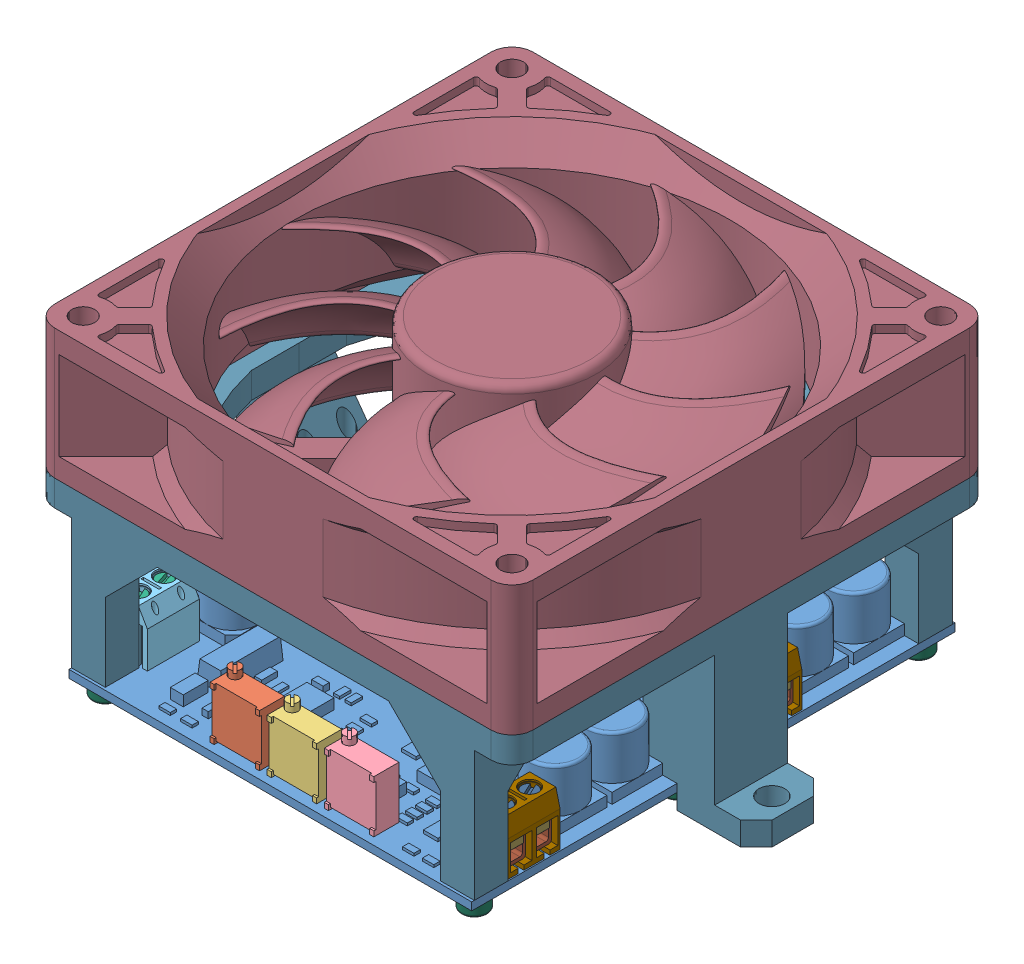
SolidWorks assembly Ensamblaje5, configuration Predeterminado. Lengths in mm.
Overall size (103.83 62.67 98.14).
56 component instances, 15 part files, 30 mates.
Components (placement in the parent):
- LTC 3780 Mudule v11-1: LTC 3780 Mudule v11 [Predeterminado] at (-9.7259 -4.7467 77.5) x (1 0 0) z (0 1 0) size (77.5 46.5 15.68)
  - LTC 3780 Mudule-1: LTC 3780 Mudule [Predeterminado] at origin size (77.5 46.5 14)
  - Trimpot_3296W v1-1: Trimpot_3296W v1 [Predeterminado] at (-8.265 -19.415 0) x (-1 0 0) z (0 0 1) size (9.53 4.83 14.15)
  - Trimpot_3296W v1 (1)-1: Trimpot_3296W v1 (1) [Predeterminado] at (2.735 -19.415 0) x (-1 0 0) z (0 0 1) size (9.53 4.83 14.15)
  - Trimpot_3296W v1 (2)-1: Trimpot_3296W v1 (2) [Predeterminado] at (13.735 -19.415 0) x (-1 0 0) z (0 0 1) size (9.53 4.83 14.15)
  - DG306-5 v2-1: DG306-5 v2 [Predeterminado] at (0 0 17) size (7.6 10.62 14.13)
    - Case-1: Case [Predeterminado] at (-38.5 -6 -17) x (0 -1 0) z (-1 0 0) size (10.62 10 7.6)
    - Screw-1: Screw [Predeterminado] at (-35.14 -8.5 -13.12) x (0.304322 -0.952569 0) z (-0.952569 -0.304322 0) size (3.38 5.66 3.38)
    - Terminal-1: Terminal [Predeterminado] at (-32.9 -6.55 -16.126) x (0 -1 0) z (-1 0 0) size (3.9 9.8 4.48)
    - Spring-1: Spring [Predeterminado] at (-37.5 -7.135 -13.226) x (0 -1 0) z (-1 0 0) size (2.73 2.2 5.76)
    - Screw-2: Screw [Predeterminado] at (-35.14 -13.5 -13.12) x (0.425528 -0.904945 0) z (-0.904945 -0.425528 0) size (3.38 5.66 3.38)
    - Terminal-2: Terminal [Predeterminado] at (-32.9 -11.55 -16.126) x (0 -1 0) z (-1 0 0) size (3.9 9.8 4.48)
    - Spring-2: Spring [Predeterminado] at (-37.5 -12.135 -13.226) x (0 -1 0) z (-1 0 0) size (2.73 2.2 5.76)
  - DG306-5 v2 (1)-1: DG306-5 v2 (1) [Predeterminado] at origin size (7.6 10.62 14.13)
    - Case (1)-1: Case (1) [Predeterminado] at (38.5 -16 0) x (0 1 0) z (1 0 0) size (10.62 10 7.6)
    - Screw (1)-1: Screw (1) [Predeterminado] at (35.14 -13.5 3.88) x (-0.304322 0.952569 0) z (0.952569 0.304322 0) size (3.38 5.66 3.38)
    - Terminal (1)-1: Terminal (1) [Predeterminado] at (32.9 -15.45 0.874) x (0 1 0) z (1 0 0) size (3.9 9.8 4.48)
    - Spring (1)-1: Spring (1) [Predeterminado] at (37.5 -14.865 3.774) x (0 1 0) z (1 0 0) size (2.73 2.2 5.76)
    - Screw (1)-2: Screw (1) [Predeterminado] at (35.14 -8.5 3.88) x (-0.425528 0.904945 0) z (0.904945 0.425528 0) size (3.38 5.66 3.38)
    - Terminal (1)-2: Terminal (1) [Predeterminado] at (32.9 -10.45 0.874) x (0 1 0) z (1 0 0) size (3.9 9.8 4.48)
    - Spring (1)-2: Spring (1) [Predeterminado] at (37.5 -9.865 3.774) x (0 1 0) z (1 0 0) size (2.73 2.2 5.76)
- LTC 3780 Mudule v11-2: LTC 3780 Mudule v11 [Predeterminado] at (-9.7259 -4.7467 124) x (1 0 0) z (0 1 0) size (77.5 46.5 15.68)
  - LTC 3780 Mudule-1: LTC 3780 Mudule [Predeterminado] at origin size (77.5 46.5 14)
  - Trimpot_3296W v1-1: Trimpot_3296W v1 [Predeterminado] at (-8.265 -19.415 0) x (-1 0 0) z (0 0 1) size (9.53 4.83 14.15)
  - Trimpot_3296W v1 (1)-1: Trimpot_3296W v1 (1) [Predeterminado] at (2.735 -19.415 0) x (-1 0 0) z (0 0 1) size (9.53 4.83 14.15)
  - Trimpot_3296W v1 (2)-1: Trimpot_3296W v1 (2) [Predeterminado] at (13.735 -19.415 0) x (-1 0 0) z (0 0 1) size (9.53 4.83 14.15)
  - DG306-5 v2-1: DG306-5 v2 [Predeterminado] at (0 0 17) size (7.6 10.62 14.13)
    - Case-1: Case [Predeterminado] at (-38.5 -6 -17) x (0 -1 0) z (-1 0 0) size (10.62 10 7.6)
    - Screw-1: Screw [Predeterminado] at (-35.14 -8.5 -13.12) x (0.304322 -0.952569 0) z (-0.952569 -0.304322 0) size (3.38 5.66 3.38)
    - Terminal-1: Terminal [Predeterminado] at (-32.9 -6.55 -16.126) x (0 -1 0) z (-1 0 0) size (3.9 9.8 4.48)
    - Spring-1: Spring [Predeterminado] at (-37.5 -7.135 -13.226) x (0 -1 0) z (-1 0 0) size (2.73 2.2 5.76)
    - Screw-2: Screw [Predeterminado] at (-35.14 -13.5 -13.12) x (0.425528 -0.904945 0) z (-0.904945 -0.425528 0) size (3.38 5.66 3.38)
    - Terminal-2: Terminal [Predeterminado] at (-32.9 -11.55 -16.126) x (0 -1 0) z (-1 0 0) size (3.9 9.8 4.48)
    - Spring-2: Spring [Predeterminado] at (-37.5 -12.135 -13.226) x (0 -1 0) z (-1 0 0) size (2.73 2.2 5.76)
  - DG306-5 v2 (1)-1: DG306-5 v2 (1) [Predeterminado] at origin size (7.6 10.62 14.13)
    - Case (1)-1: Case (1) [Predeterminado] at (38.5 -16 0) x (0 1 0) z (1 0 0) size (10.62 10 7.6)
    - Screw (1)-1: Screw (1) [Predeterminado] at (35.14 -13.5 3.88) x (-0.304322 0.952569 0) z (0.952569 0.304322 0) size (3.38 5.66 3.38)
    - Terminal (1)-1: Terminal (1) [Predeterminado] at (32.9 -15.45 0.874) x (0 1 0) z (1 0 0) size (3.9 9.8 4.48)
    - Spring (1)-1: Spring (1) [Predeterminado] at (37.5 -14.865 3.774) x (0 1 0) z (1 0 0) size (2.73 2.2 5.76)
    - Screw (1)-2: Screw (1) [Predeterminado] at (35.14 -8.5 3.88) x (-0.425528 0.904945 0) z (0.904945 0.425528 0) size (3.38 5.66 3.38)
    - Terminal (1)-2: Terminal (1) [Predeterminado] at (32.9 -10.45 0.874) x (0 1 0) z (1 0 0) size (3.9 9.8 4.48)
    - Spring (1)-2: Spring (1) [Predeterminado] at (37.5 -9.865 3.774) x (0 1 0) z (1 0 0) size (2.73 2.2 5.76)
- 92mm FAN-1: 92mm FAN [Default] at (-9.7259 50.2533 100.75) x (1 0 0) z (0 0 -1) size (98.99 31.34 98.14)
- soporte-1: soporte [Predeterminado] at (-9.7259 20.2533 100.75) size (100 34.5 92)
- Tornillo M3x10_2-1: Tornillo M3x10_2 [Predeterminado] at (-45.2259 3.7533 97) x (1 0 0) z (0 -1 0) size (5 5 13)
- Tornillo M3x10_2-2: Tornillo M3x10_2 [Predeterminado] at (25.7741 3.7533 58) x (1 0 0) z (0 -1 0) size (5 5 13)
- Tornillo M3x10_2-3: Tornillo M3x10_2 [Predeterminado] at (-45.2259 3.7533 143.5) x (1 0 0) z (0 -1 0) size (5 5 13)
- Tornillo M3x10_2-4: Tornillo M3x10_2 [Predeterminado] at (25.7741 3.7533 143.5) x (1 0 0) z (0 -1 0) size (5 5 13)
- Tornillo M3x10_2-5: Tornillo M3x10_2 [Predeterminado] at (25.7741 3.7533 97) x (1 0 0) z (0 -1 0) size (5 5 13)
- Tornillo M3x10_2-6: Tornillo M3x10_2 [Predeterminado] at (25.7741 3.7533 104.5) x (1 0 0) z (0 -1 0) size (5 5 13)
- Tornillo M3x10_2-7: Tornillo M3x10_2 [Predeterminado] at (-45.2259 3.7533 58) x (1 0 0) z (0 -1 0) size (5 5 13)
- Tornillo M3x10_2-8: Tornillo M3x10_2 [Predeterminado] at (-45.2259 3.7533 104.5) x (1 0 0) z (0 -1 0) size (5 5 13)
- Tornillo M3x10_2-9: Tornillo M3x10_2 [Predeterminado] at (-50.9759 19.2533 142) x (1 0 0) z (0 1 0) size (5 5 13)
- Tornillo M3x10_2-10: Tornillo M3x10_2 [Predeterminado] at (31.5241 19.2533 59.5) x (1 0 0) z (0 1 0) size (5 5 13)
- Tornillo M3x10_2-11: Tornillo M3x10_2 [Predeterminado] at (31.5241 19.2533 142) x (1 0 0) z (0 1 0) size (5 5 13)
- Tornillo M3x10_2-12: Tornillo M3x10_2 [Predeterminado] at (-50.9759 19.2533 59.5) x (1 0 0) z (0 1 0) size (5 5 13)
Mates (geometry in assembly coordinates):
- Ancho1: width anti-aligned: plane of 92mm FAN-1 through (36.2741 25.2533 54.75) normal (0 0 -1); plane of 92mm FAN-1 through (36.2741 25.2533 146.75) normal (0 0 1); plane of LTC 3780 Mudule v11-2/LTC 3780 Mudule-1 through (-48.4759 85.6331 147.25) normal (0 0 1); plane of LTC 3780 Mudule v11-1/LTC 3780 Mudule-1 through (-48.4759 85.6331 54.25) normal (0 0 -1)
- Ancho2: width anti-aligned: plane of 92mm FAN-1 through (-55.7259 25.2533 54.75) normal (-1 0 0); plane of 92mm FAN-1 through (36.2741 25.2533 54.75) normal (1 0 0); plane of LTC 3780 Mudule v11-2/LTC 3780 Mudule-1 through (29.0241 85.6331 100.75) normal (1 0 0); plane of LTC 3780 Mudule v11-2/LTC 3780 Mudule-1 through (-48.4759 85.6331 100.75) normal (-1 0 0)
- Distancia1: distance = 30 mm anti-aligned: plane of 92mm FAN-1 through (-9.7259 25.2533 100.75) normal (0 -1 0); plane of LTC 3780 Mudule v11-1/LTC 3780 Mudule-1 through (-9.7259 -4.7467 77.5) normal (0 1 0)
- Coincidente1: coincident anti-aligned: plane of 92mm FAN-1 through (-9.7259 25.2533 100.75) normal (0 -1 0); plane of soporte-1 through (-9.7259 25.2533 100.75) normal (0 1 0)
- Coincidente2: coincident aligned: plane of 92mm FAN-1 through (-55.7259 25.2533 54.75) normal (-1 0 0); plane of soporte-1 through (-55.7259 25.2533 146.75) normal (-1 0 0)
- Coincidente3: coincident aligned: plane of 92mm FAN-1 through (36.2741 25.2533 54.75) normal (0 0 -1); plane of soporte-1 through (-55.7259 25.2533 54.75) normal (0 0 -1)
- Coincidente4: coincident aligned: plane of Tornillo M3x10_2-6 through (25.7741 -9.2467 104.5) normal (0 -1 0); plane of Tornillo M3x10_2-7 through (-45.2259 -9.2467 58) normal (0 -1 0)
- Coincidente5: coincident aligned: plane of Tornillo M3x10_2-5 through (25.7741 -9.2467 97) normal (0 -1 0); plane of Tornillo M3x10_2-7 through (-45.2259 -9.2467 58) normal (0 -1 0)
- Coincidente6: coincident aligned: plane of Tornillo M3x10_2-7 through (-45.2259 -9.2467 58) normal (0 -1 0); plane of Tornillo M3x10_2-8 through (-45.2259 -9.2467 104.5) normal (0 -1 0)
- Coincidente7: coincident aligned: plane of Tornillo M3x10_2-3 through (-45.2259 -9.2467 143.5) normal (0 -1 0); plane of Tornillo M3x10_2-8 through (-45.2259 -9.2467 104.5) normal (0 -1 0)
- Coincidente8: coincident aligned: plane of Tornillo M3x10_2-1 through (-45.2259 -9.2467 97) normal (0 -1 0); plane of Tornillo M3x10_2-3 through (-45.2259 -9.2467 143.5) normal (0 -1 0)
- Coincidente9: coincident aligned: plane of Tornillo M3x10_2-1 through (-45.2259 -9.2467 97) normal (0 -1 0); plane of Tornillo M3x10_2-4 through (25.7741 -9.2467 143.5) normal (0 -1 0)
- Coincidente10: coincident aligned: plane of Tornillo M3x10_2-2 through (25.7741 -9.2467 58) normal (0 -1 0); plane of Tornillo M3x10_2-4 through (25.7741 -9.2467 143.5) normal (0 -1 0)
- Coincidente11: coincident anti-aligned: plane of LTC 3780 Mudule v11-2/LTC 3780 Mudule-1 through (-9.7259 -6.2467 124) normal (0 -1 0); plane of Tornillo M3x10_2-3 through (-45.2259 -6.2467 143.5) normal (0 1 0)
- Concéntrica1: concentric anti-aligned: cylinder of LTC 3780 Mudule v11-2/LTC 3780 Mudule-1 through (-45.2259 85.6331 143.5) axis (0 -1 0) radius 1.9; cylinder of Tornillo M3x10_2-3 through (-45.2259 -9.2467 143.5) axis (0 1 0) radius 2.5
- Concéntrica2: concentric anti-aligned: cylinder of LTC 3780 Mudule v11-2/LTC 3780 Mudule-1 through (-45.2259 85.6331 104.5) axis (0 -1 0) radius 1.9; cylinder of Tornillo M3x10_2-8 through (-45.2259 -9.2467 104.5) axis (0 1 0) radius 2.5
- Concéntrica3: concentric anti-aligned: cylinder of LTC 3780 Mudule v11-1/LTC 3780 Mudule-1 through (-45.2259 85.6331 97) axis (0 -1 0) radius 1.9; cylinder of Tornillo M3x10_2-1 through (-45.2259 -9.2467 97) axis (0 1 0) radius 2.5
- Concéntrica4: concentric anti-aligned: cylinder of LTC 3780 Mudule v11-1/LTC 3780 Mudule-1 through (-45.2259 85.6331 58) axis (0 -1 0) radius 1.9; cylinder of Tornillo M3x10_2-7 through (-45.2259 -9.2467 58) axis (0 1 0) radius 2.5
- Concéntrica5: concentric anti-aligned: cylinder of LTC 3780 Mudule v11-2/LTC 3780 Mudule-1 through (25.7741 85.6331 104.5) axis (0 -1 0) radius 1.9; cylinder of Tornillo M3x10_2-6 through (25.7741 -9.2467 104.5) axis (0 1 0) radius 2.5
- Concéntrica6: concentric anti-aligned: cylinder of LTC 3780 Mudule v11-2/LTC 3780 Mudule-1 through (25.7741 85.6331 143.5) axis (0 -1 0) radius 1.9; cylinder of Tornillo M3x10_2-4 through (25.7741 -9.2467 143.5) axis (0 1 0) radius 2.5
- Concéntrica7: concentric anti-aligned: cylinder of LTC 3780 Mudule v11-1/LTC 3780 Mudule-1 through (25.7741 85.6331 97) axis (0 -1 0) radius 1.9; cylinder of Tornillo M3x10_2-5 through (25.7741 -9.2467 97) axis (0 1 0) radius 2.5
- Concéntrica8: concentric anti-aligned: cylinder of LTC 3780 Mudule v11-1/LTC 3780 Mudule-1 through (25.7741 85.6331 58) axis (0 -1 0) radius 1.9; cylinder of Tornillo M3x10_2-2 through (25.7741 -9.2467 58) axis (0 1 0) radius 2.5
- Coincidente12: coincident aligned: plane of Tornillo M3x10_2-10 through (31.5241 32.2533 59.5) normal (0 1 0); plane of Tornillo M3x10_2-11 through (31.5241 32.2533 142) normal (0 1 0)
- Coincidente13: coincident aligned: plane of Tornillo M3x10_2-10 through (31.5241 32.2533 59.5) normal (0 1 0); plane of Tornillo M3x10_2-12 through (-50.9759 32.2533 59.5) normal (0 1 0)
- Coincidente14: coincident aligned: plane of Tornillo M3x10_2-9 through (-50.9759 32.2533 142) normal (0 1 0); plane of Tornillo M3x10_2-12 through (-50.9759 32.2533 59.5) normal (0 1 0)
- Coincidente15: coincident anti-aligned: plane of 92mm FAN-1 through (-9.7259 29.2533 100.75) normal (0 1 0); plane of Tornillo M3x10_2-9 through (-50.9759 29.2533 142) normal (0 -1 0)
- Concéntrica9: concentric aligned: cylinder of 92mm FAN-1 through (-50.9759 59.2533 142) axis (0 -1 0) radius 2.2; cylinder of Tornillo M3x10_2-9 through (-50.9759 32.2533 142) axis (0 -1 0) radius 2.5
- Concéntrica10: concentric aligned: cylinder of 92mm FAN-1 through (-50.9759 59.2533 59.5) axis (0 -1 0) radius 2.2; cylinder of Tornillo M3x10_2-12 through (-50.9759 32.2533 59.5) axis (0 -1 0) radius 2.5
- Concéntrica11: concentric aligned: cylinder of 92mm FAN-1 through (31.5241 59.2533 142) axis (0 -1 0) radius 2.2; cylinder of Tornillo M3x10_2-11 through (31.5241 32.2533 142) axis (0 -1 0) radius 2.5
- Concéntrica12: concentric aligned: cylinder of 92mm FAN-1 through (31.5241 59.2533 59.5) axis (0 -1 0) radius 2.2; cylinder of Tornillo M3x10_2-10 through (31.5241 32.2533 59.5) axis (0 -1 0) radius 2.5
